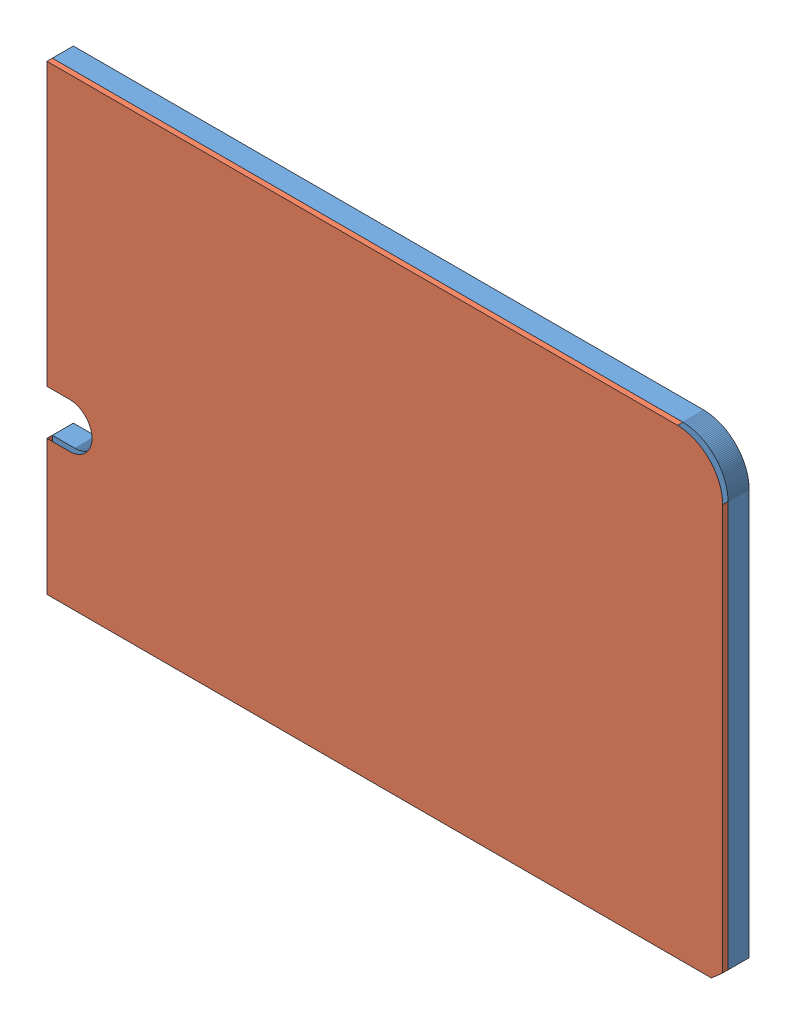
SolidWorks assembly marker_test1, configuration Standard. Lengths in mm.
Overall size (150 102.5 5.87).
4 component instances, 2 part files, 0 mates.
Components (placement in the parent):
- marker_test1.step-1: marker_test1.step [Standard] at origin size (150 102.5 4.67)
  - marker_test1.step.step-1: marker_test1.step.step [Standard] at (-40 -40 0) x (1 0 0) z (0 0 -1) size (150 102.5 4.67)
    - PCB.step.step-1: PCB.step.step [Standard] at origin size (150 102.5 4.67)
- marker_test-1: marker_test [Standard] at origin size (150 102.5 1.6)
